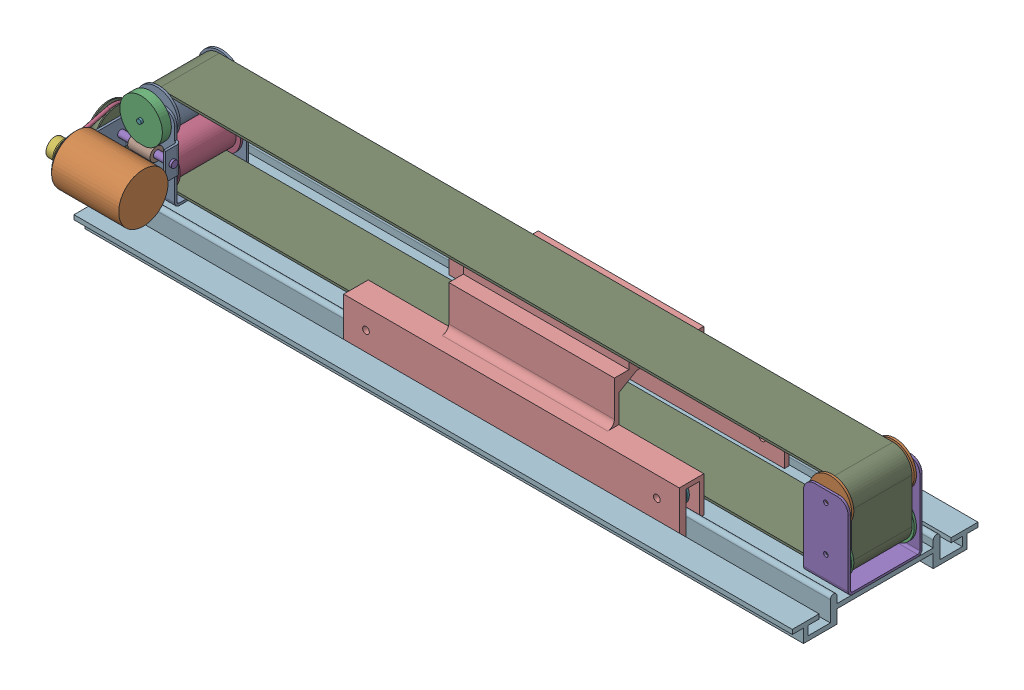
SolidWorks assembly 05_ToneArm_Drive, configuration Default. Lengths in mm.
Overall size (332.22 49 92).
23 component instances, 15 part files, 0 mates.
Components (placement in the parent):
- 01_Carrier-1: 01_Carrier [Default] at origin size (321 49 83)
  - Roller.1.2-1: Roller.1.2 [Default] at (-301 0 0) size (19 19 29)
  - Roller.1.2-2: Roller.1.2 [Default] at origin size (19 19 29)
  - Roller.1.2-3: Roller.1.2 [Default] at (0 -20 0) size (19 19 29)
  - Roller.1.2-4: Roller.1.2 [Default] at (-301 -20 0) size (19 19 29)
  - Bracket.2-1: Bracket.2 [Default] at (175 0 0) size (20 36.5 33)
  - Wheel.2-1: Wheel.2 [Default] at (118 0 0) size (12 12 5)
  - Wheel.2-2: Wheel.2 [Default] at (248 58.6314 -492.1127) x (1 0 0) z (0 0 -1) size (12 12 5)
  - Wheel.2-3: Wheel.2 [Default] at (248 58.6314 -538.1127) x (1 0 0) z (0 0 -1) size (12 12 5)
  - Belt-1: Belt [Default] at origin size (318 37 27)
  - Carrier-1: Carrier [Default] at (258 0 0) size (150 43.5 64)
  - Wheel.2-4: Wheel.2 [Default] at (118 0 46) size (12 12 5)
  - RailProfile-1: RailProfile [Default] at origin size (321 12.5 83)
- 02_Drive-1: 02_Drive [Default] at origin size (40.22 41 68)
  - Bracket.1-1: Bracket.1 [Default] at (-126 0 0) size (24 36.5 66)
  - Motor-1: Motor [Default] at origin size (40.22 22 22)
  - Gear.1-1: Gear.1 [Default] at (0 0 1) size (19 19 4)
  - Band-1: Band [Default] at origin size (1.5 20 35)
  - Worm_Axle-1: Worm_Axle [Default] at (10 -2 0) size (30 3 3)
  - Wheel_C-1: Wheel_C [Default] at (-0.5 0 0) size (8 10 10)
  - Axle.1-1: Axle.1 [Default] at origin size (2 2 40)
  - Worm-1: Worm [Default] at (10 -2 0) size (10 6 6)
  - Wheel_B-1: Wheel_B [Default] at (-0.5 0 0) size (4 20 20)
